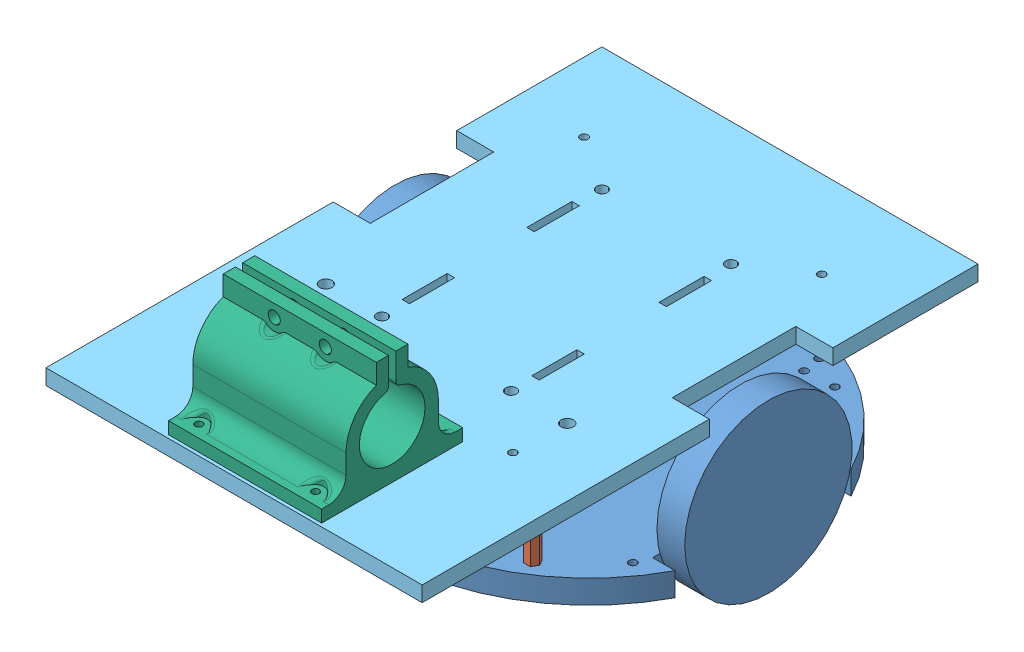
SolidWorks assembly RSLKAss, configuration Default. Lengths in mm.
Overall size (154.69 120.83 228.6).
12 component instances, 6 part files, 31 mates.
Components (placement in the parent):
- RSLKRobot-1: RSLKRobot [Default] at (-48.6373 76.7378 171.8377) size (153.54 68.83 162.51)
- 1inHexSpacer-1: 1inHexSpacer [Default] at (-16.032 111.7898 197.7688) x (0.5 0 0.866025) z (0.866025 0 -0.5) size (5.57 31.75 4.83)
- 1inHexSpacer-3: 1inHexSpacer [Default] at (67.9824 111.7898 197.7688) x (0.5 0 0.866025) z (0.866025 0 -0.5) size (5.57 31.75 4.83)
- .75inHexSpacer-1: .75inHexSpacer [Default] at (52.5182 129.7222 100.832) x (1 0 0) z (0 0 -1) size (5.57 25.4 4.83)
- .75inHexSpacer-2: .75inHexSpacer [Default] at (-0.5678 129.7222 191.0274) x (1 0 0) z (0 0 -1) size (5.57 25.4 4.83)
- .75inHexSpacer-3: .75inHexSpacer [Default] at (52.5182 129.7222 191.0274) x (1 0 0) z (0 0 -1) size (5.57 25.4 4.83)
- .75inHexSpacer-4: .75inHexSpacer [Default] at (-0.5678 129.7222 100.832) x (1 0 0) z (0 0 -1) size (5.57 25.4 4.83)
- 1inHexSpacer-4: 1inHexSpacer [Default] at (-2.6646 111.7898 204.6548) x (0.5 0 0.866025) z (0.866025 0 -0.5) size (5.57 31.75 4.83)
- 1inHexSpacer-5: 1inHexSpacer [Default] at (54.615 111.7898 204.6548) x (0.5 0 0.866025) z (0.866025 0 -0.5) size (5.57 31.75 4.83)
- RSLKSpacePlate-1: RSLKSpacePlate [Default] at (67.9824 114.9648 197.7688) x (-1 0 0) z (0 0 -1) size (108.14 17.78 33.54)
- RSLKBasePlate-2: RSLKBasePlate [Default] at (-0.5678 129.7222 191.276) size (154.69 6.35 228.6)
- MotorMount-1: MotorMount [Default] at (-2.3457 156.0722 248.282) x (0 -1 0) z (1 0 0) size (46 58 63)
Mates (geometry in assembly coordinates):
- Coincident1: coincident anti-aligned: plane of RSLKRobot-1 through (-48.6373 86.3898 171.8377) normal (0 1 0); plane of 1inHexSpacer-1 through (-16.032 86.3898 197.7688) normal (0 -1 0)
- Parallel1: parallel aligned: plane of RSLKRobot-1 through (-3.1713 110.6722 193.6309) normal (0 0 1); plane of 1inHexSpacer-1 through (-14.6388 86.3898 200.1818) normal (0 0 1)
- Concentric2: concentric anti-aligned: cylinder of RSLKRobot-1 through (-16.032 86.3898 197.7688) axis (0 -1 0) radius 1.5875; cylinder of 1inHexSpacer-1 through (-16.032 80.0398 197.7688) axis (0 1 0) radius 1.016
- Coincident3: coincident anti-aligned: plane of RSLKRobot-1 through (-48.6373 86.3898 171.8377) normal (0 1 0); plane of 1inHexSpacer-3 through (67.9824 86.3898 197.7688) normal (0 -1 0)
- Concentric3: concentric anti-aligned: cylinder of RSLKRobot-1 through (67.9824 86.3898 197.7688) axis (0 -1 0) radius 1.5875; cylinder of 1inHexSpacer-3 through (67.9824 80.0398 197.7688) axis (0 1 0) radius 1.016
- Parallel3: parallel aligned: plane of RSLKRobot-1 through (-3.1713 110.6722 193.6309) normal (0 0 1); plane of 1inHexSpacer-3 through (69.3756 86.3898 200.1818) normal (0 0 1)
- Concentric4: concentric aligned: cylinder of RSLKRobot-1 through (52.5182 109.2498 100.832) axis (0 1 0) radius 1.5875; cylinder of .75inHexSpacer-1 through (52.5182 104.3222 100.832) axis (0 1 0) radius 1.016
- Parallel4: parallel anti-aligned: plane of RSLKRobot-1 through (-3.1713 110.6722 98.2285) normal (0 0 -1); plane of .75inHexSpacer-1 through (53.9114 110.6722 103.245) normal (0 0 1)
- Coincident7: coincident anti-aligned: plane of RSLKRobot-1 through (-48.6373 110.6722 171.8377) normal (0 1 0); plane of .75inHexSpacer-1 through (52.5182 110.6722 100.832) normal (0 -1 0)
- Concentric5: concentric aligned: circle of RSLKRobot-1; cylinder of .75inHexSpacer-4 through (-0.5678 104.3222 100.832) axis (0 1 0) radius 1.016
- Concentric6: concentric aligned: cylinder of RSLKRobot-1 through (52.5182 109.2498 191.0274) axis (0 1 0) radius 1.5875; cylinder of .75inHexSpacer-3 through (52.5182 104.3222 191.0274) axis (0 1 0) radius 1.016
- Concentric7: concentric aligned: circle of RSLKRobot-1; cylinder of .75inHexSpacer-2 through (-0.5678 104.3222 191.0274) axis (0 1 0) radius 1.016
- Coincident8: coincident anti-aligned: plane of RSLKRobot-1 through (-48.6373 110.6722 171.8377) normal (0 1 0); plane of .75inHexSpacer-2 through (-0.5678 110.6722 191.0274) normal (0 -1 0)
- Coincident9: coincident anti-aligned: plane of RSLKRobot-1 through (-48.6373 110.6722 171.8377) normal (0 1 0); plane of .75inHexSpacer-3 through (52.5182 110.6722 191.0274) normal (0 -1 0)
- Coincident10: coincident anti-aligned: plane of RSLKRobot-1 through (-48.6373 110.6722 171.8377) normal (0 1 0); plane of .75inHexSpacer-4 through (-0.5678 110.6722 100.832) normal (0 -1 0)
- Coincident11: coincident aligned: plane of .75inHexSpacer-1 through (51.1251 110.6722 98.419) normal (0 0 -1); plane of .75inHexSpacer-4 through (-1.9609 110.6722 98.419) normal (0 0 -1)
- Coincident12: coincident aligned: plane of .75inHexSpacer-2 through (0.8254 110.6722 193.4404) normal (0 0 1); plane of .75inHexSpacer-3 through (53.9114 110.6722 193.4404) normal (0 0 1)
- Concentric8: concentric anti-aligned: cylinder of RSLKRobot-1 through (54.615 86.3898 204.6548) axis (0 -1 0) radius 1.5875; cylinder of 1inHexSpacer-5 through (54.615 80.0398 204.6548) axis (0 1 0) radius 1.016
- Coincident13: coincident anti-aligned: plane of RSLKRobot-1 through (-48.6373 86.3898 171.8377) normal (0 1 0); plane of 1inHexSpacer-5 through (54.615 86.3898 204.6548) normal (0 -1 0)
- Coincident14: coincident anti-aligned: plane of RSLKRobot-1 through (-48.6373 86.3898 171.8377) normal (0 1 0); plane of 1inHexSpacer-4 through (-2.6646 86.3898 204.6548) normal (0 -1 0)
- Concentric9: concentric anti-aligned: cylinder of RSLKRobot-1 through (-2.6646 86.3898 204.6548) axis (0 -1 0) radius 1.5875; cylinder of 1inHexSpacer-4 through (-2.6646 80.0398 204.6548) axis (0 1 0) radius 1.016
- Coincident16: coincident aligned: plane of 1inHexSpacer-4 through (-1.2714 86.3898 207.0678) normal (0 0 1); plane of 1inHexSpacer-5 through (56.0082 86.3898 207.0678) normal (0 0 1)
- Concentric11: concentric anti-aligned: cylinder of 1inHexSpacer-1 through (-16.032 105.4398 197.7688) axis (0 1 0) radius 1.016; cylinder of RSLKSpacePlate-1 through (-16.032 135.2848 197.7688) axis (0 -1 0) radius 4.7625
- Concentric12: concentric anti-aligned: cylinder of 1inHexSpacer-3 through (67.9824 105.4398 197.7688) axis (0 1 0) radius 1.016; cylinder of RSLKSpacePlate-1 through (67.9824 135.2848 197.7688) axis (0 -1 0) radius 4.7625
- Coincident17: coincident anti-aligned: plane of 1inHexSpacer-3 through (67.9824 111.7898 197.7688) normal (0 1 0); plane of RSLKSpacePlate-1 through (67.9824 111.7898 197.7688) normal (0 -1 0)
- Concentric13: concentric anti-aligned: cylinder of .75inHexSpacer-1 through (52.5182 123.3722 100.832) axis (0 1 0) radius 1.016; cylinder of RSLKBasePlate-1 through (52.5182 136.0722 100.832) axis (0 -1 0) radius 2.2225
- Coincident18: coincident anti-aligned: plane of .75inHexSpacer-1 through (52.5182 129.7222 100.832) normal (0 1 0); plane of RSLKBasePlate-1 through (-0.5678 129.7222 191.276) normal (0 -1 0)
- Concentric14: concentric aligned: circle of .75inHexSpacer-4; circle of RSLKBasePlate-1
- Coincident19: coincident anti-aligned: plane of RSLKBasePlate-1 through (-0.5678 136.0722 191.276) normal (0 1 0); plane of MotorMount-1 through (-2.3457 136.0722 229.282) normal (0 -1 0)
- Concentric15: concentric aligned: cylinder of RSLKBasePlate-1 through (5.1543 118.2922 272.282) axis (0 1 0) radius 1.5875; cylinder of MotorMount-1 through (5.1543 131.0722 272.282) axis (0 1 0) radius 1.5
- Concentric16: concentric aligned: cylinder of RSLKBasePlate-1 through (5.1543 118.2922 224.282) axis (0 1 0) radius 1.5875; cylinder of MotorMount-1 through (5.1543 131.0722 224.282) axis (0 1 0) radius 1.5
